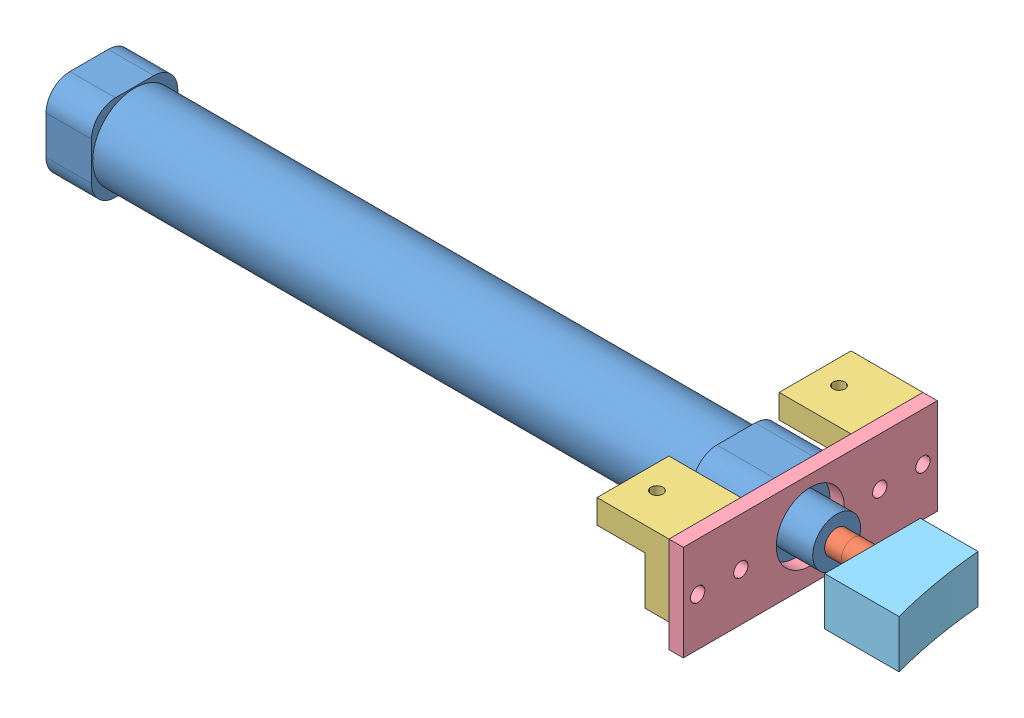
SolidWorks assembly 推环装置（带角码）左, configuration 默认. Lengths in mm.
Overall size (181.03 20 53).
8 component instances, 5 part files, 12 mates.
Components (placement in the parent):
- 推环装置（单）-1: 推环装置（单） [默认] at (-56.5649 147.9384 -82.2692) size (175.5 18 18)
  - 16x100标准型-1: 16x100标准型 [默认] at (-234.5005 -21.5583 173.7409) x (0 0 -1) z (1 0 0) size (18 18 175.5)
    - 16x100标准型壳-1: 16x100标准型壳 [默认] at (-1.7591 0.557 78) size (18 18 156)
    - 16x100标准型轴-1: 16x100标准型轴 [默认] at (-1.7591 0.557 87.5) x (0.935449 -0.353463 0) z (0 0 1) size (5 5 166)
- 单孔角码-1: 单孔角码 [默认] at (-80.5654 131.4371 119.7308) x (0 0 -1) z (0 -1 0) size (15 15 15)
- 气缸固定前板-1: 气缸固定前板 [默认] at (-65.5654 136.4371 66.7308) x (1 0 0) z (0 0 -1) size (3 20 53)
- 单孔角码-2: 单孔角码 [默认] at (-80.5654 131.4371 81.7308) x (0 0 -1) z (0 -1 0) size (15 15 15)
- 推环块-1: 推环块 [默认] at (-47.5654 121.9371 75.2308) x (0 1 0) z (0 0 -1) size (10 15.53 20)
Mates (geometry in assembly coordinates):
- 同心1: concentric aligned: circle of 推环装置（单）-1/16x100标准型-1/16x100标准型壳-1; circle of 气缸固定前板-1
- 同心2: concentric aligned: circle of 气缸固定前板-1; circle of 单孔角码-2
- 同心3: concentric aligned: circle of 气缸固定前板-1; circle of 单孔角码-2
- 重合2: coincident anti-aligned: plane of 气缸固定前板-1 through (-65.5654 136.4371 66.7308) normal (-1 0 0); plane of 单孔角码-2 through (-65.5654 131.4371 81.7308) normal (1 0 0)
- 同心4: concentric aligned: cylinder of 单孔角码-1 through (-70.5654 126.4371 116.7308) axis (1 0 0) radius 1.25; circle of 气缸固定前板-1
- 同心5: concentric aligned: circle of 单孔角码-1; circle of 气缸固定前板-1
- 重合3: coincident anti-aligned: plane of 单孔角码-1 through (-65.5654 131.4371 119.7308) normal (1 0 0); plane of 气缸固定前板-1 through (-65.5654 136.4371 66.7308) normal (-1 0 0)
- 平行2: parallel aligned: line of 推环装置（单）-1/16x100标准型-1/16x100标准型壳-1 through (-65.5654 117.9371 97.2308) axis (0 0 -1); line of 气缸固定前板-1 through (-65.5654 116.4371 119.7308) axis (0 0 -1)
- 重合7: coincident anti-aligned: plane of 推环装置（单）-1/16x100标准型-1/16x100标准型壳-1 through (-65.5654 126.9371 93.2308) normal (1 0 0); plane of 气缸固定前板-1 through (-65.5654 136.4371 66.7308) normal (-1 0 0)
- 平行4: parallel: line of 气缸固定前板-1 through (-62.5654 116.4371 119.7308) axis (0 0 -1); line of 推环块-1 through (-31.6719 121.9371 85.2308) axis (0 0 1)
- 同心6: concentric: cylinder of 推环装置（单）-1/16x100标准型-1/16x100标准型轴-1 through (-37.5654 126.9371 93.2308) axis (-1 0 0) radius 2.5; cylinder of 推环块-1 through (-37.5654 126.9371 93.2308) axis (-1 0 0) radius 3
- 重合12: coincident anti-aligned: plane of 推环装置（单）-1/16x100标准型-1/16x100标准型轴-1 through (-37.5654 126.9371 93.2308) normal (1 0 0); plane of 推环块-1 through (-37.5654 126.9371 93.2308) normal (-1 0 0)
